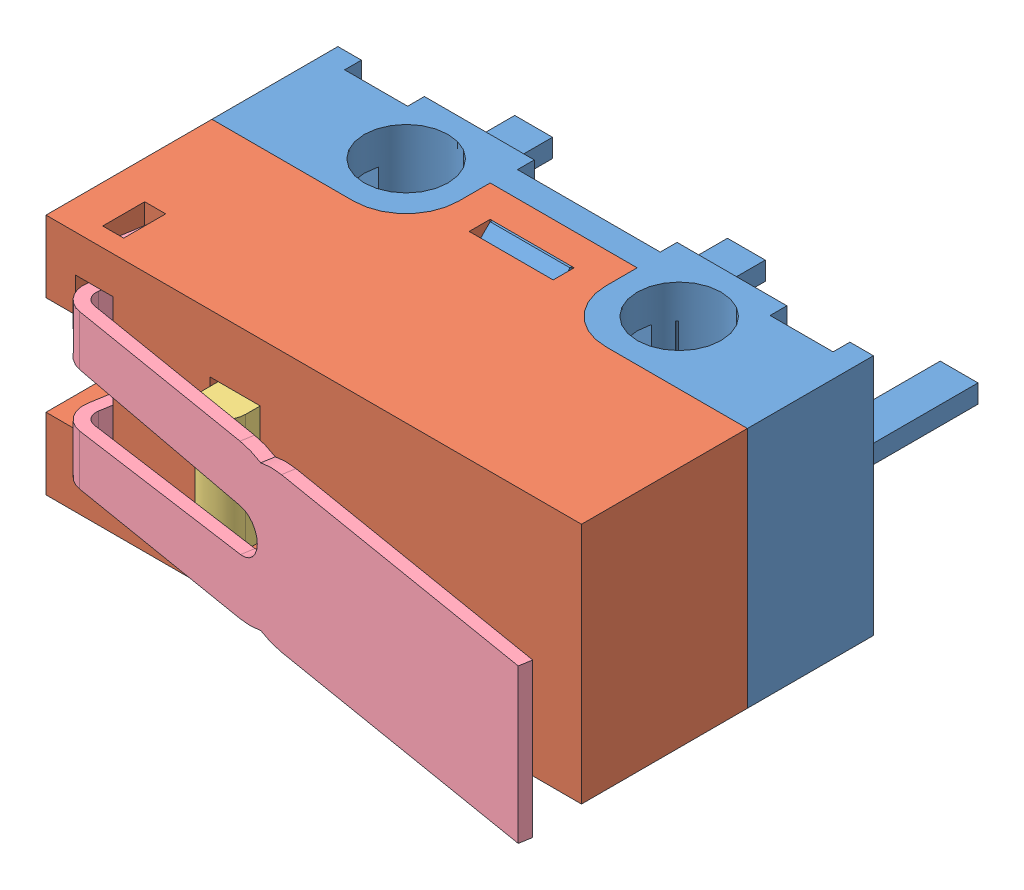
SolidWorks assembly capteur, configuration Défaut. Lengths in mm.
Overall size (14.18 5.77 12.92).
4 component instances, 4 part files, 11 mates.
Components (placement in the parent):
- piece26-1: piece26 [Défaut] at (1.6738 0.6186 2.775) size (12.75 5.77 7.15)
- piece 28-1: piece 28 [Défaut] at (1.6738 0.6186 0.775) size (12.75 5.77 5.95)
- piece27-2: piece27 [Défaut] at (-0.2012 0.6186 2.975) size (1 2.8 4.5)
- piece29-1: piece29 [Défaut] at (-3.3489 0.6186 5.3357) x (0.986417 0 0.164259) z (-0.164259 0 0.986417) size (13.3 5.06 1.9)
Mates (geometry in assembly coordinates):
- Coïncidente1: coincident anti-aligned: plane of piece26-1 through (1.6738 3.0036 0.775) normal (0 0 1); plane of piece 28-1 through (-4.7012 -2.2664 0.775) normal (0 0 -1)
- Coïncidente2: coincident anti-aligned: plane of piece26-1 through (7.5488 3.0036 3.575) normal (0 1 0); plane of piece 28-1 through (-4.7012 3.0036 6.725) normal (0 -1 0)
- Coïncidente3: coincident aligned: plane of piece26-1 through (-4.7012 3.5036 -0.225) normal (-1 0 0); plane of piece 28-1 through (-4.7012 3.5036 6.725) normal (-1 0 0)
- Distance2: distance = 0.1 mm anti-aligned: plane of piece 28-1 through (0.3988 2.1186 0.775) normal (-1 0 0); plane of piece27-2 through (0.2988 2.0186 2.975) normal (1 0 0)
- Distance1: distance = 0.1 mm anti-aligned: plane of piece 28-1 through (-0.8012 -0.8814 0.775) normal (0 1 0); plane of piece27-2 through (-0.2012 -0.7814 6.975) normal (0 -1 0)
- Distance3: distance = 0.25 mm: plane of piece 28-1 through (-4.7012 -2.2664 6.725) normal (0 0 1); axis of piece27-2 through (-0.2012 2.0186 6.975) axis (0 -1 0)
- Tangent1: tangent anti-aligned: cylinder of piece27-2 through (-0.2012 2.0186 6.975) axis (0 -1 0) radius 0.5; plane of piece29-1 through (-3.3158 2.4486 6.9632) normal (0.164259 0 -0.986417)
- Coïncidente12: coincident aligned: plane of piece 28-1; plane of piece29-1
- Coïncidente13: coincident: plane of piece 28-1 through (-3.8012 -2.2664 5.275) normal (1 0 0); line of piece29-1 through (-3.8012 3.1486 6.2257) axis (0 -1 0)
- Tangent2: tangent anti-aligned: cylinder of piece27-2 through (-0.2012 2.0186 6.975) axis (0 -1 0) radius 0.5; plane of piece29-1 through (-3.3158 2.4486 6.9632) normal (0.164259 0 -0.986417)
- Coïncidente15: coincident: plane of piece 28-1 through (-3.8012 -2.2664 6.275) normal (0 0 -1); line of piece29-1 through (-3.5053 -1.9114 6.275) axis (0 1 0)
